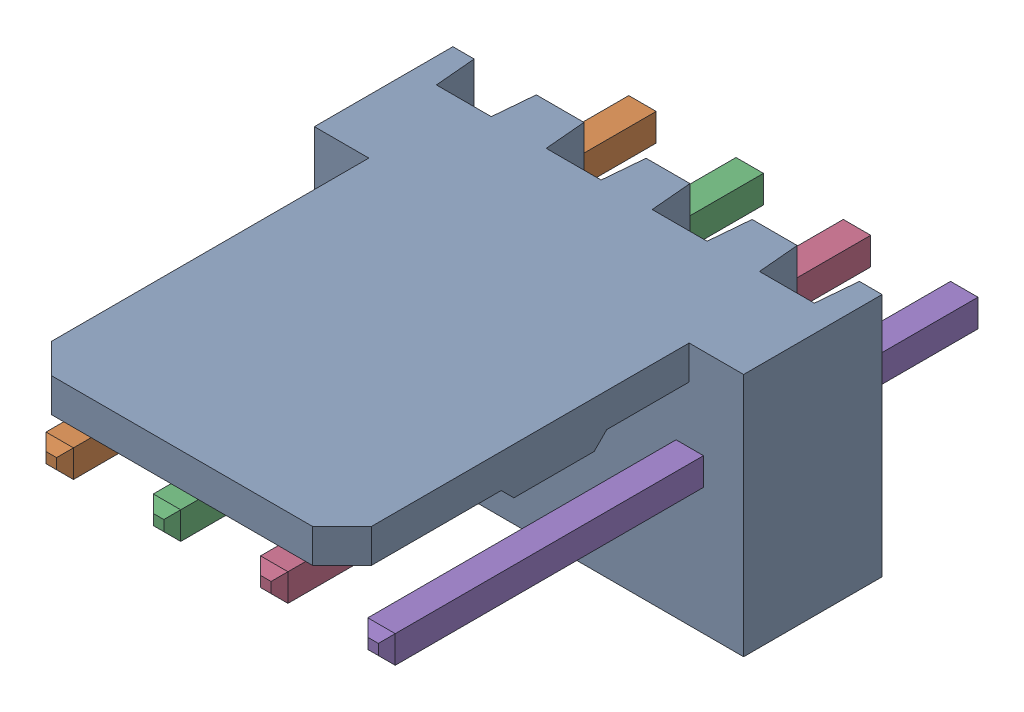
SolidWorks assembly Molex PCB 4 pin v3_6, configuration Predeterminado. Lengths in mm.
Overall size (10.16 5.79 14.92).
5 component instances, 2 part files, 0 mates.
Components (placement in the parent):
- BASE9710016-1: BASE9710016 [Predeterminado] at (2.54 2.895 -8.22) size (10.16 5.79 11.5)
- PINO9710016-1: PINO9710016 [Predeterminado] at (1.27 3.325 -0.72) size (0.65 0.65 14.2)
- PINO9710016-2: PINO9710016 [Predeterminado] at (3.81 3.325 -0.72) size (0.65 0.65 14.2)
- PINO9710016-3: PINO9710016 [Predeterminado] at (6.35 3.325 -0.72) size (0.65 0.65 14.2)
- PINO9710016-4: PINO9710016 [Predeterminado] at (8.89 3.325 -0.72) size (0.65 0.65 14.2)
